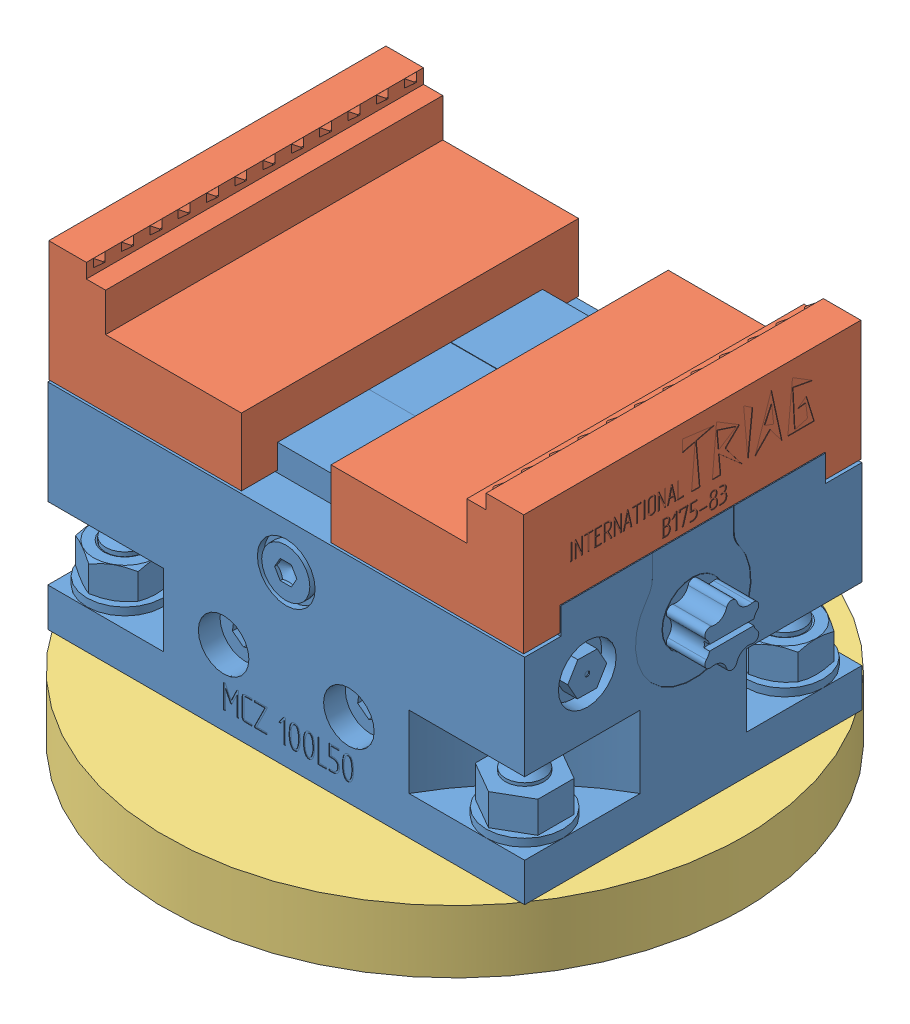
SolidWorks assembly ETAU 63-83mm, configuration Défaut. Lengths in mm.
Overall size (120 83 120).
4 component instances, 3 part files, 11 mates.
Components (placement in the parent):
- Copie de MCZ 100L50_KS^ETAU 63-83mm-1: Copie de MCZ 100L50_KS^ETAU 63-83mm [Défaut] at (0 0 30) size (107 62 70.1) (virtual)
- Copie de B175-83_KS^ETAU 63-83mm-1: Copie de B175-83_KS^ETAU 63-83mm [Défaut] at (41.55 43.436 0) x (0 0 -1) z (0 1 0) size (70 40 25) (virtual)
- Copie de B175-83_KS^ETAU 63-83mm-2: Copie de B175-83_KS^ETAU 63-83mm [Défaut] at (-41.55 43.436 0) x (0 0 1) z (0 1 0) size (70 40 25) (virtual)
- Copie de BASE ADAPT^ETAU 63-83mm-1: Copie de BASE ADAPT^ETAU 63-83mm [Défaut] at (0 -37.064 0) x (1 0 0) z (0 1 0) size (120 120 13) (virtual)
Mates (geometry in assembly coordinates):
- Coïncidente1: coincident aligned: plane of Copie de MCZ 100L50_KS^ETAU 63-83mm-1 through (0 0 30) normal (1 0 0); plane of assembly through (0 0 0) normal (1 0 0)
- Coïncidente3: coincident aligned: plane of Copie de MCZ 100L50_KS^ETAU 63-83mm-1 through (0 0 0) normal (0 0 1); plane of assembly through (0 0 0) normal (0 0 1)
- Coïncidente4: coincident aligned: plane of Copie de MCZ 100L50_KS^ETAU 63-83mm-1 through (0 0 30) normal (0 1 0); plane of assembly through (0 0 0) normal (0 1 0)
- Coïncidente5: coincident anti-aligned: plane of Copie de B175-83_KS^ETAU 63-83mm-1 through (41.55 43.436 0) normal (0 0 -1); plane of assembly through (0 0 0) normal (0 0 1)
- Coïncidente6: coincident aligned: plane of Copie de B175-83_KS^ETAU 63-83mm-2 through (-41.55 43.436 0) normal (0 0 1); plane of assembly through (0 0 0) normal (0 0 1)
- Coïncidente7: coincident anti-aligned: plane of Copie de MCZ 100L50_KS^ETAU 63-83mm-1 through (49 25.936 0) normal (0 1 0); plane of Copie de B175-83_KS^ETAU 63-83mm-1 through (43.6 25.936 18.15) normal (0 -1 0)
- Coïncidente9: coincident anti-aligned: plane of Copie de MCZ 100L50_KS^ETAU 63-83mm-1 through (49 25.936 0) normal (0 1 0); plane of Copie de B175-83_KS^ETAU 63-83mm-2 through (-43.6 25.936 -18.15) normal (0 -1 0)
- Symétrique1: symmetric aligned: plane of Copie de MCZ 100L50_KS^ETAU 63-83mm-1 through (0 0 30) normal (1 0 0); plane of Copie de B175-83_KS^ETAU 63-83mm-2 through (-41.5 46.086 -38.5) normal (1 0 0); plane of Copie de B175-83_KS^ETAU 63-83mm-1 through (41.5 46.086 38.5) normal (-1 0 0)
- Distance1: distance = 83 mm anti-aligned: plane of Copie de B175-83_KS^ETAU 63-83mm-1 through (41.5 46.086 38.5) normal (-1 0 0); plane of Copie de B175-83_KS^ETAU 63-83mm-2 through (-41.5 46.086 -38.5) normal (1 0 0)
- Coïncidente10: coincident anti-aligned: plane of Copie de MCZ 100L50_KS^ETAU 63-83mm-1 through (10 -24.064 0) normal (0 -1 0); plane of Copie de BASE ADAPT^ETAU 63-83mm-1 through (0 -24.064 0) normal (0 1 0)
- Coaxiale1: concentric aligned: cylinder of Copie de MCZ 100L50_KS^ETAU 63-83mm-1 through (0 -22.064 0) axis (0 -1 0) radius 11.7378; cylinder of Copie de BASE ADAPT^ETAU 63-83mm-1 through (0 -24.064 0) axis (0 -1 0) radius 60
